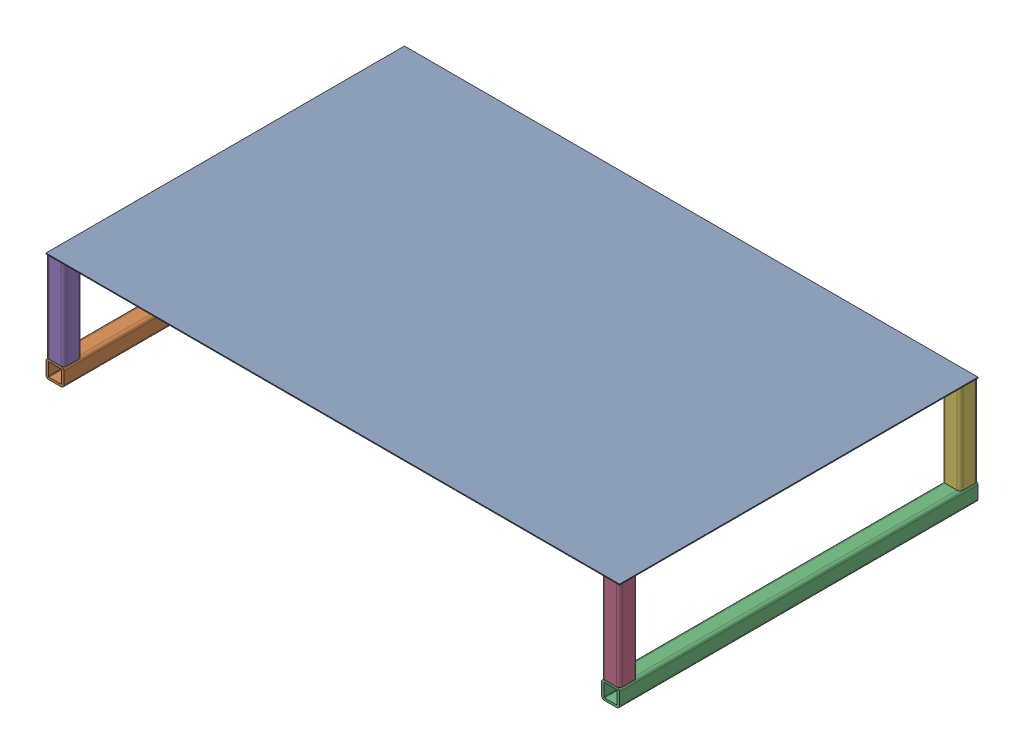
SolidWorks assembly Bottom Tray Assembly, configuration Default. Lengths in mm.
Overall size (406.4 76.81 254).
7 component instances, 3 part files, 18 mates.
Components (placement in the parent):
- Perforated Tray-1: Perforated Tray [92725T36] at (-209.6714 56.3674 72.3455) size (406.4 0.61 254)
- Tray Base-1: Tray Base [89825K319] at (-406.5214 -13.7874 72.3455) size (12.7 12.7 254)
- Tray Base-2: Tray Base [89825K319] at (-12.8214 -13.7874 72.3455) size (12.7 12.7 254)
- Tray Sides-1: Tray Sides [89825K319] at (-12.8214 24.3126 192.9955) x (1 0 0) z (0 -1 0) size (12.7 12.7 63.5)
- Tray Sides-2: Tray Sides [89825K319] at (-406.5214 24.3126 192.9955) x (1 0 0) z (0 -1 0) size (12.7 12.7 63.5)
- Tray Sides-3: Tray Sides [89825K319] at (-12.8214 24.3126 -48.3045) x (1 0 0) z (0 -1 0) size (12.7 12.7 63.5)
- Tray Sides-4: Tray Sides [89825K319] at (-406.5214 24.3126 -48.3045) x (1 0 0) z (0 -1 0) size (12.7 12.7 63.5)
Mates (geometry in assembly coordinates):
- Coincident1: coincident anti-aligned: plane of Tray Base-2 through (-8.5351 -7.4374 199.3455) normal (0 1 0); plane of Tray Sides-1 through (-8.5351 -7.4374 188.7093) normal (0 -1 0)
- Coincident2: coincident aligned: plane of Tray Base-2 through (-6.4714 -18.0736 199.3455) normal (1 0 0); plane of Tray Sides-1 through (-6.4714 -7.4374 188.7093) normal (1 0 0)
- Coincident3: coincident aligned: plane of Tray Base-2 through (-8.5351 -18.0736 199.3455) normal (0 0 1); plane of Tray Sides-1 through (-8.5351 -7.4374 199.3455) normal (0 0 1)
- Coincident4: coincident anti-aligned: plane of Tray Base-2 through (-8.5351 -7.4374 199.3455) normal (0 1 0); plane of Tray Sides-3 through (-8.5351 -7.4374 -52.5907) normal (0 -1 0)
- Coincident5: coincident aligned: plane of Tray Base-2 through (-6.4714 -18.0736 199.3455) normal (1 0 0); plane of Tray Sides-3 through (-6.4714 -7.4374 -52.5907) normal (1 0 0)
- Coincident6: coincident aligned: plane of Tray Base-2 through (-8.5351 -18.0736 -54.6545) normal (0 0 -1); plane of Tray Sides-3 through (-8.5351 -7.4374 -54.6545) normal (0 0 -1)
- Coincident7: coincident anti-aligned: plane of Tray Base-1 through (-402.2351 -7.4374 199.3455) normal (0 1 0); plane of Tray Sides-2 through (-402.2351 -7.4374 188.7093) normal (0 -1 0)
- Coincident8: coincident aligned: plane of Tray Base-1 through (-402.2351 -18.0736 199.3455) normal (0 0 1); plane of Tray Sides-2 through (-402.2351 -7.4374 199.3455) normal (0 0 1)
- Coincident9: coincident aligned: plane of Tray Base-1 through (-412.8714 -18.0736 199.3455) normal (-1 0 0); plane of Tray Sides-2 through (-412.8714 -7.4374 188.7093) normal (-1 0 0)
- Coincident10: coincident anti-aligned: plane of Tray Base-1 through (-402.2351 -7.4374 199.3455) normal (0 1 0); plane of Tray Sides-4 through (-402.2351 -7.4374 -52.5907) normal (0 -1 0)
- Coincident11: coincident aligned: plane of Tray Base-1 through (-412.8714 -18.0736 199.3455) normal (-1 0 0); plane of Tray Sides-4 through (-412.8714 -7.4374 -52.5907) normal (-1 0 0)
- Coincident12: coincident aligned: plane of Tray Base-1 through (-402.2351 -18.0736 -54.6545) normal (0 0 -1); plane of Tray Sides-4 through (-402.2351 -7.4374 -54.6545) normal (0 0 -1)
- Coincident13: coincident anti-aligned: plane of Perforated Tray-1 through (-412.8714 56.0626 199.3455) normal (0 -1 0); plane of Tray Sides-2 through (-402.2351 56.0626 188.7093) normal (0 1 0)
- Coincident14: coincident anti-aligned: plane of Perforated Tray-1 through (-412.8714 56.0626 199.3455) normal (0 -1 0); plane of Tray Sides-1 through (-8.5351 56.0626 188.7093) normal (0 1 0)
- Coincident15: coincident aligned: plane of Perforated Tray-1 through (-209.6714 56.3674 199.3455) normal (0 0 1); plane of Tray Sides-2 through (-402.2351 -7.4374 199.3455) normal (0 0 1)
- Coincident16: coincident aligned: plane of Perforated Tray-1 through (-412.8714 56.0626 199.3455) normal (-1 0 0); plane of Tray Base-1 through (-412.8714 -18.0736 199.3455) normal (-1 0 0)
- Coincident17: coincident aligned: plane of Perforated Tray-1 through (-209.6714 56.3674 199.3455) normal (0 0 1); plane of Tray Sides-1 through (-8.5351 -7.4374 199.3455) normal (0 0 1)
- Coincident18: coincident aligned: plane of Perforated Tray-1 through (-6.4714 56.0626 199.3455) normal (1 0 0); plane of Tray Sides-1 through (-6.4714 -7.4374 188.7093) normal (1 0 0)
